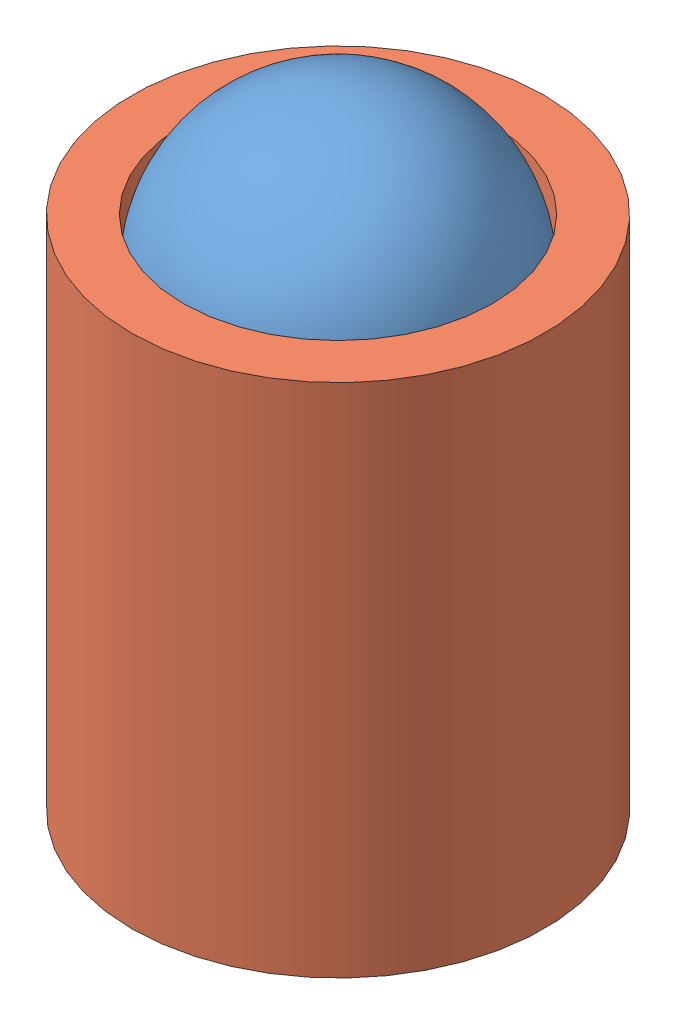
SolidWorks assembly Assem1, configuration Default. Lengths in mm.
Overall size (4.37 6.55 4.46).
2 component instances, 2 part files, 0 mates.
Components (placement in the parent):
- bearing-1: bearing [Default] at (1.0887 2.1034 0.7655) x (0.382529 0.161661 0.909691) z (0.909447 -0.239606 -0.339846) size (3 3 3)
- socket-1: socket [Default] at (1.3805 -2.0899 2.2364) size (4 5 4)
